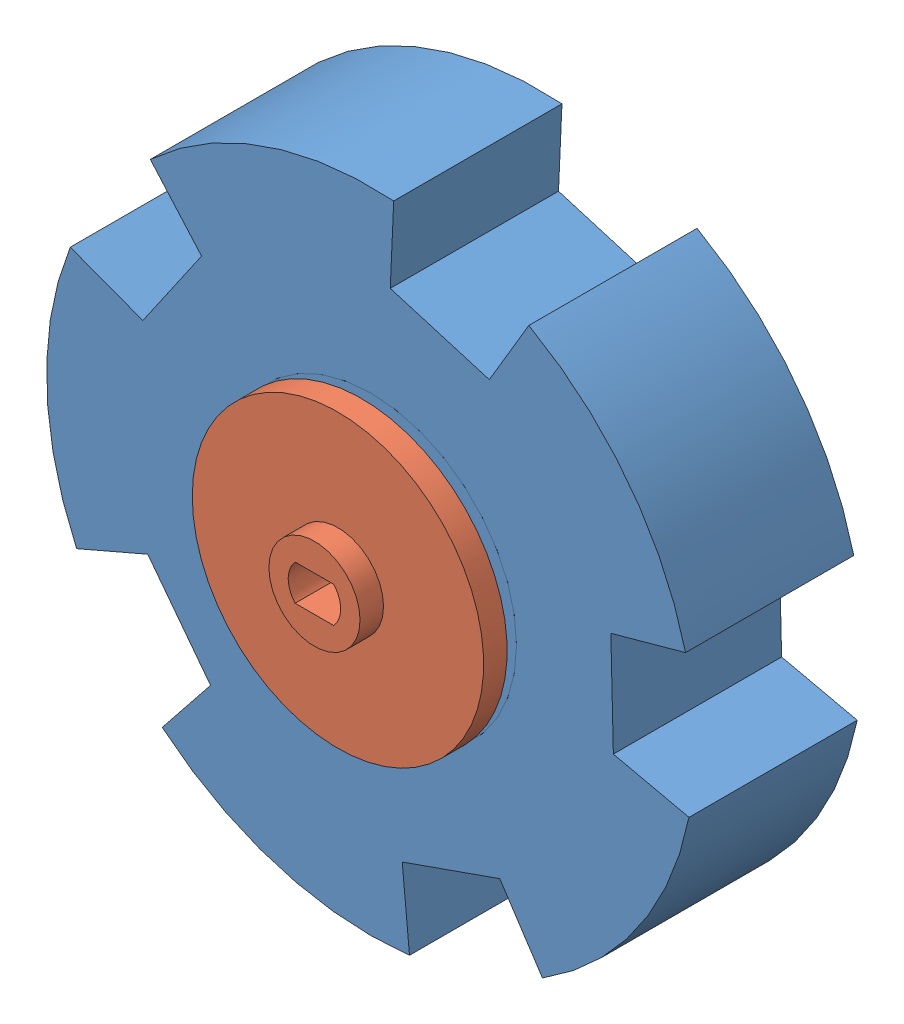
SolidWorks assembly neoprene_mount_asm, configuration Default. Lengths in mm.
Overall size (68.35 69 24.9).
2 component instances, 2 part files, 4 mates.
Components (placement in the parent):
- neoprene_wheel-1: neoprene_wheel [Default] x (1 0 0) z (0 -1 0) size (68.35 19.9 69)
- neoprene_wheel_mounting-1: neoprene_wheel_mounting [Default] at (0 0 9.95) size (31 31 6.9)
Mates (geometry in assembly coordinates):
- InPlace1: in place: plane of neoprene_wheel-1 through (0 0 9.95) normal (0 0 1); plane of neoprene_wheel_mounting-1 through (0 0 9.95) normal (0 0 1); moOrthogonalPlaneRef_w of neoprene_wheel-1 through (0 0 9.95) normal (0 0 1); plane of neoprene_wheel_mounting-1 through (0 0 9.95) normal (0 1 0); plane of neoprene_wheel-1 through (0 0 9.95) normal (0 0 1); plane of neoprene_wheel_mounting-1 through (0 0 9.95) normal (1 0 0); plane of neoprene_wheel-1 through (0 0 9.95) normal (0 0 1); unknown of neoprene_wheel_mounting-1
- Coincident1: coincident aligned: plane of neoprene_wheel-1; plane of neoprene_wheel_mounting-1
- Coincident2: coincident aligned: moOrthogonalPlaneRef_w of neoprene_wheel-1 through (0 0 9.95) normal (0 1 0); plane of neoprene_wheel_mounting-1 through (0 0 9.95) normal (0 1 0)
- Coincident3: coincident anti-aligned: moOrthogonalPlaneRef_w of neoprene_wheel-1 through (0 0 9.95) normal (-1 0 0); plane of neoprene_wheel_mounting-1 through (0 0 9.95) normal (1 0 0)
